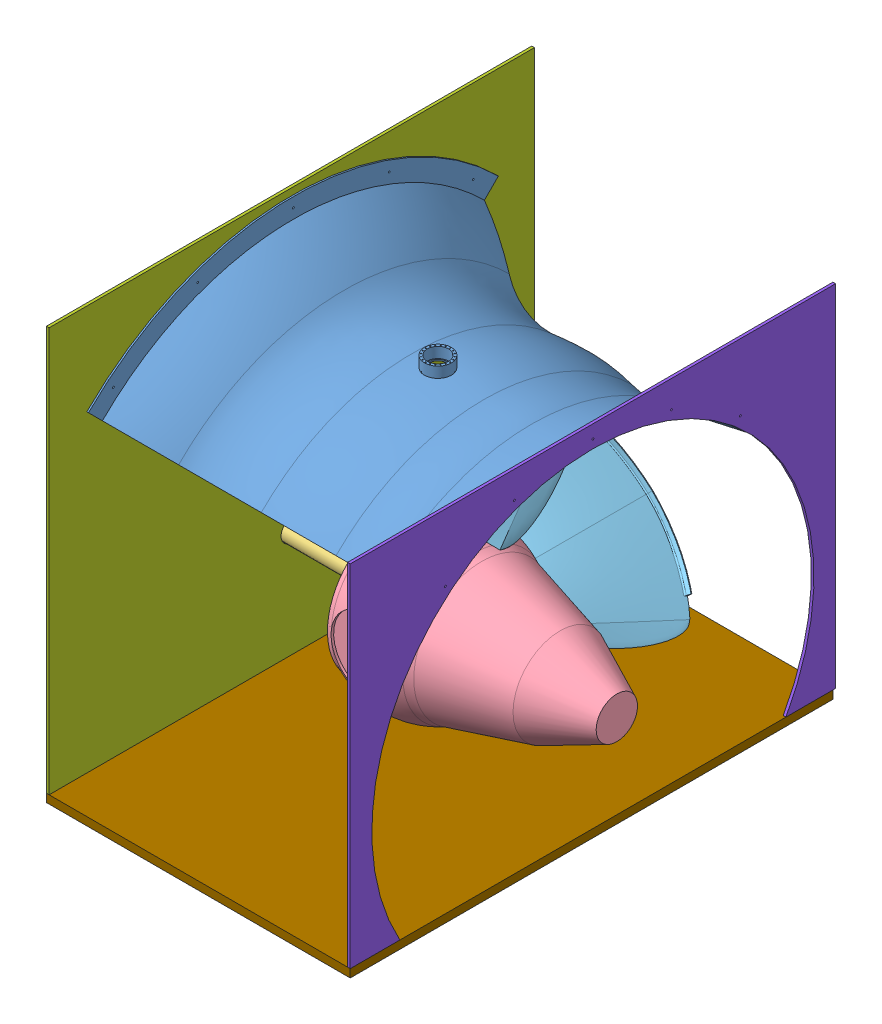
SolidWorks assembly Montagem_Maquete, configuration Valor predeterminado. Lengths in mm.
Overall size (4973.09 4973.09 6233.51).
26 component instances, 11 part files, 32 mates.
Components (placement in the parent):
- Aro_Camara-2: Aro_Camara [Valor predeterminado] at origin size (1106.8 535.11 1520.28)
- Disco-1: Disco [Valor predeterminado] at origin size (10 496 496)
- Eixo-1: Eixo [Valor predeterminado] at (-605 0 0) x (1 0 0) z (0 0.214688 0.976683) size (600 76.2 76.2)
- Rotor-1: Rotor [Valor predeterminado] at origin size (814.2 581.81 541.32)
- Pa_da_Turbina-1: Pa_da_Turbina [Valor predeterminado<Como usinado>] at (0 227.7653 0) x (0.707107 0 0.707107) z (-0.707107 0 0.707107) size (1330 2890.82 5703.01)
- Flange-2: Flange [Valor predeterminado] at (-5 0 0) x (0 1 0) z (0 0 1) size (192.8 44.8 192.8)
- Placa_de_Fixacao-2: Placa_de_Fixacao [Valor predeterminado] at (-552 350 0) x (0 -1 0) z (1 0 0) size (1500 1800 10)
- Placa_Suporte-1: Placa_Suporte [Valor predeterminado] at (564.8 -400 0) x (0 0 -1) z (1 0 0) size (1800 1300 10)
- Placa_Base-1: Placa_Base [Valor predeterminado] at (11.4 -430 5) x (0 0 -1) z (1 0 0) size (1790 30 1126.8)
- Pa_da_Turbina-2: Pa_da_Turbina [Valor predeterminado<Como usinado>] at (0 0 -227.7653) x (0.707107 0.707107 0) z (-0.707107 0.707107 0) size (1330 2890.82 5703.01)
- socket head cap screw_din-2: socket head cap screw_din [DIN 912 M6 x 30 --- 30N] at (-24.8 73.7 0) size (36 10 10)
- hex nut style 1 gradeab_din-1: hex nut style 1 gradeab_din [Hexagon Nut ISO 4032 - M6 - D - N] at (10.2 73.7 0) x (0 0 -1) z (1 0 0) size (10 11.55 5.2)
- hex nut style 1 gradeab_din-2: hex nut style 1 gradeab_din [Hexagon Nut ISO 4032 - M6 - D - N] at (10.2 0 -73.7) x (0 -1 0) z (1 0 0) size (10 11.55 5.2)
- hex nut style 1 gradeab_din-3: hex nut style 1 gradeab_din [Hexagon Nut ISO 4032 - M6 - D - N] at (10.2 -73.7 0) x (0 0 1) z (1 0 0) size (10 11.55 5.2)
- hex nut style 1 gradeab_din-4: hex nut style 1 gradeab_din [Hexagon Nut ISO 4032 - M6 - D - N] at (10.2 0 73.7) x (0 1 0) z (1 0 0) size (10 11.55 5.2)
- socket head cap screw_din-3: socket head cap screw_din [DIN 912 M6 x 30 --- 30N] at (-24.8 0 -73.7) x (1 0 0) z (0 1 0) size (36 10 10)
- socket head cap screw_din-4: socket head cap screw_din [DIN 912 M6 x 30 --- 30N] at (-24.8 -73.7 0) x (1 0 0) z (0 0 -1) size (36 10 10)
- socket head cap screw_din-5: socket head cap screw_din [DIN 912 M6 x 30 --- 30N] at (-24.8 0 73.7) x (1 0 0) z (0 -1 0) size (36 10 10)
- socket head cap screw_din-10: socket head cap screw_din [DIN 912 M6 x 25 --- 25N] at (-11 240.8953 0) x (1 0 0) z (0 0.980922 0.194404) size (31 10 10)
- hex nut style 1 gradeab_din-5: hex nut style 1 gradeab_din [Hexagon Nut ISO 4032 - M6 - D - N] at (16.2005 240.8953 0) x (0 0 -1) z (1 0 0) size (10 11.55 5.2)
- socket head cap screw_din-11: socket head cap screw_din [DIN 912 M6 x 25 --- 25N] at (-11 0 -240.8953) x (1 0 0) z (0 0.194404 -0.980922) size (31 10 10)
- socket head cap screw_din-12: socket head cap screw_din [DIN 912 M6 x 25 --- 25N] at (-11 -240.8953 0) x (1 0 0) z (0 -0.980922 -0.194404) size (31 10 10)
- socket head cap screw_din-13: socket head cap screw_din [DIN 912 M6 x 25 --- 25N] at (-11 0 240.8953) x (1 0 0) z (0 -0.194404 0.980922) size (31 10 10)
- hex nut style 1 gradeab_din-6: hex nut style 1 gradeab_din [Hexagon Nut ISO 4032 - M6 - D - N] at (16.2005 0 -240.8953) x (0 -1 0) z (1 0 0) size (10 11.55 5.2)
- hex nut style 1 gradeab_din-7: hex nut style 1 gradeab_din [Hexagon Nut ISO 4032 - M6 - D - N] at (16.2005 -240.8953 0) x (0 0 1) z (1 0 0) size (10 11.55 5.2)
- hex nut style 1 gradeab_din-8: hex nut style 1 gradeab_din [Hexagon Nut ISO 4032 - M6 - D - N] at (16.2005 0 240.8953) x (0 1 0) z (1 0 0) size (10 11.55 5.2)
Mates (geometry in assembly coordinates):
- Coincidente24: coincident: point of ?
- Coincidente25: coincident aligned: plane of Rotor-1 through (0 0 0) normal (1 0 0); plane of assembly through (0 0 0) normal (1 0 0)
- Paralelo1: parallel anti-aligned: plane of Rotor-1 through (50 253.8953 0) normal (0 1 0); plane of Pa_da_Turbina-1 through (-35.3553 255.8953 35.3553) normal (0 -1 0)
- Ângulo1: planar angle = 0.785398 rad aligned: plane of Rotor-1 through (0 0 0) normal (0 0 1); plane of Pa_da_Turbina-1 through (0 227.7653 0) normal (-0.707107 0 0.707107)
- Concêntrico7: concentric aligned: cylinder of Rotor-1 through (0 -141.1401 0) axis (0 -1 0) radius 133; cylinder of Pa_da_Turbina-1 through (0 227.7653 0) axis (0 -1 0) radius 133
- Concêntrico5: concentric aligned: circle of Aro_Camara-2; cylinder of Placa_de_Fixacao-2 through (-552 0 0) axis (1 0 0) radius 40
- Coincidente27: coincident anti-aligned: plane of Aro_Camara-2 through (-542 706.7317 -706.7317) normal (-1 0 0); plane of Placa_de_Fixacao-2 through (-542 350 0) normal (1 0 0)
- Coincidente28: coincident aligned: plane of Rotor-1 through (0 0 0) normal (0 1 0); plane of assembly through (0 0 0) normal (0 1 0)
- Concêntrico6: concentric anti-aligned: cylinder of Placa_de_Fixacao-2 through (-552 0 0) axis (1 0 0) radius 40; cylinder of Eixo-1 through (-605 0 0) axis (-1 0 0) radius 38.1
- Concêntrico82: concentric anti-aligned: cylinder of Eixo-1 through (-605 0 0) axis (-1 0 0) radius 33.3; cylinder of Flange-2 through (-5 0 0) axis (1 0 0) radius 38.1
- Coincidente302: coincident anti-aligned: plane of Disco-1 through (-5 248 0) normal (-1 0 0); plane of Flange-2 through (-5 38.1 0) normal (1 0 0)
- Concêntrico831: concentric aligned: cylinder of Flange-2 through (-18.8 73.7 0) axis (-1 0 0) radius 3.3; cylinder of socket head cap screw_din-2 through (-56.55 73.7 0) axis (-1 0 0) radius 5
- Coincidente3031: coincident anti-aligned: plane of Flange-2 through (-18.8 96.4 0) normal (-1 0 0); plane of socket head cap screw_din-2 through (-18.8 78.7 0) normal (1 0 0)
- Concêntrico84: concentric anti-aligned: cylinder of Disco-1 through (-18.8 73.7 0) axis (-1 0 0) radius 3.3; cylinder of hex nut style 1 gradeab_din-1 through (-14.8375 73.7 0) axis (1 0 0) radius 3
- Coincidente304: coincident anti-aligned: plane of Disco-1 through (5 248 0) normal (1 0 0); plane of hex nut style 1 gradeab_din-1 through (5 73.7 10) normal (-1 0 0)
- Coincidente3033: coincident anti-aligned: plane of Disco-1 through (-5 248 0) normal (-1 0 0); plane of Eixo-1 through (-5 37.2116 -8.1796) normal (1 0 0)
- Concêntrico833: concentric anti-aligned: circle of Aro_Camara-2; circle of Placa_Suporte-1
- Coincidente3034: coincident anti-aligned: plane of Aro_Camara-2 through (564.8 582.0366 -582.0366) normal (1 0 0); plane of Placa_Suporte-1 through (564.8 0 0) normal (-1 0 0)
- Coincidente3035: coincident anti-aligned: plane of Placa_de_Fixacao-2; plane of assembly through (0 0 0) normal (0 0 1)
- Coincidente3036: coincident anti-aligned: plane of Rotor-1 through (15 268.8953 0) normal (0 1 0); plane of Pa_da_Turbina-1 through (-35.3553 268.8953 35.3553) normal (0 -1 0)
- Coincidente3037: coincident anti-aligned: plane of Placa_de_Fixacao-2 through (-542 -400 900) normal (0 -1 0); plane of Placa_Base-1 through (11.4 -400 5) normal (0 1 0)
- Coincidente3038: coincident: plane of Placa_de_Fixacao-2 through (-542 1100 900) normal (0 0 1); line of Placa_Base-1 through (-552 -400 900) axis (1 0 0)
- Coincidente3039: coincident aligned: plane of Placa_de_Fixacao-2 through (-552 350 0) normal (-1 0 0); plane of Placa_Base-1 through (-552 -400 900) normal (-1 0 0)
- Coincidente3040: coincident anti-aligned: plane of Placa_Suporte-1 through (564.8 -400 0) normal (0 0 -1); plane of assembly through (0 0 0) normal (0 0 1)
- Concêntrico8341: concentric anti-aligned: cylinder of Disco-1 through (11.0005 240.8953 0) axis (1 0 0) radius 3.3; cylinder of socket head cap screw_din-10 through (-42.75 240.8953 0) axis (-1 0 0) radius 5
- Coincidente30411: coincident anti-aligned: plane of Disco-1 through (-5 248 0) normal (-1 0 0); plane of socket head cap screw_din-10 through (-5 241.8673 -4.9046) normal (1 0 0)
- Coincidente30421: coincident anti-aligned: plane of Rotor-1 through (11.0005 232.8953 0) normal (1 0 0); plane of hex nut style 1 gradeab_din-5 through (11.0005 240.8953 10) normal (-1 0 0)
- Concêntrico836: concentric anti-aligned: cylinder of socket head cap screw_din-10 through (-42.75 240.8953 0) axis (-1 0 0) radius 3; cylinder of hex nut style 1 gradeab_din-5 through (11.0005 240.8953 0) axis (1 0 0) radius 2.5
- Concêntrico8342: concentric anti-aligned: cylinder of Eixo-1 through (-605 0 0) axis (-1 0 0) radius 38.1; cylinder of ? through (-552 0 0) axis (1 0 0) radius 50
- Coincidente30422: coincident anti-aligned: plane of Placa_de_Fixacao-2 through (-552 350 0) normal (-1 0 0); plane of ? through (-552 36.2412 -11.7551) normal (1 0 0)
- Concêntrico8343: concentric aligned: cylinder of Eixo-1 through (-605 0 0) axis (-1 0 0) radius 38.1; cylinder of ? through (-542 0 0) axis (-1 0 0) radius 38.1
- Coincidente30423: coincident anti-aligned: plane of Placa_de_Fixacao-2 through (-542 350 0) normal (1 0 0); plane of ? through (-542 -24.7031 29.0064) normal (-1 0 0)
